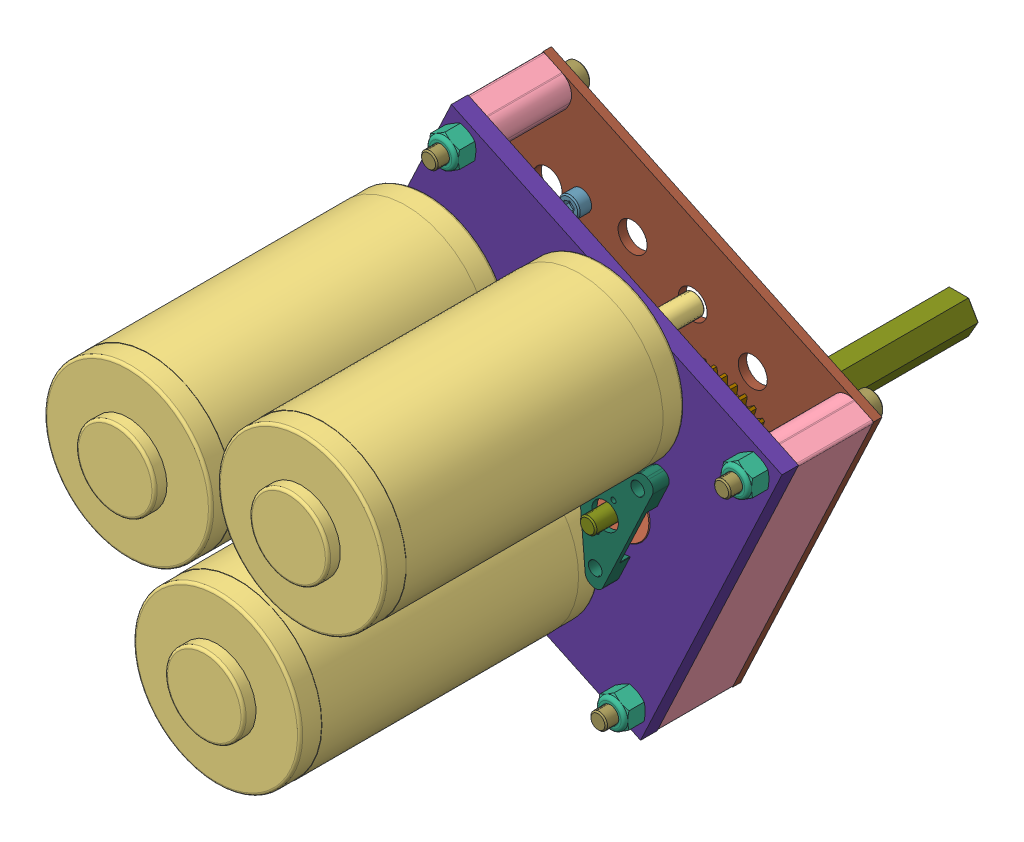
SolidWorks assembly 3CIM Gearbox - AM14U, configuration Default. Lengths in mm.
Overall size (180.67 174.39 248.76).
30 component instances, 17 part files, 62 mates.
Components (placement in the parent):
- 500 E-klip-1: 500 E-klip [Default] at (16.1298 77.6456 -43.9601) x (-0.987566 -0.157207 0) z (0 0 1) size (19.07 20.96 1.27)
- FR6ZZ Bearing-1: FR6ZZ Bearing [Default] at (-13.0875 102.2889 -55.8473) x (0.991783 0.127931 0) z (0 0 -1) size (24.69 24.69 7.16)
- CIM Motor SW-1: CIM Motor SW [Default] at (-100.8929 87.6226 -3.2185) x (0 1 0) z (0 0 -1) size (64.01 64.01 154.94)
- ex-2508 Spacer-1: ex-2508 Spacer [Default] at (-92.2921 67.2369 -57.3713) x (0.425715 0.904857 0) z (0 0 1) size (127 14.35 28.75)
- CIM Motor SW-2: CIM Motor SW [Default] at (-101.4872 6.1263 -3.2185) x (-0.762709 0.646742 0) z (0 0 -1) size (64.01 64.01 154.94)
- Toughbox 14T Small Cluster-1: Toughbox 14T Small Cluster [Default] at (-21.1033 95.1629 -40.7851) x (-0.837052 0.547123 0) z (0 0 -1) size (20.03 20.32 15.25)
- 14-20 Nylock Nut_97135A210-1: 14-20 Nylock Nut_97135A210 [Default] at (19.7748 14.5119 -22.2685) x (1 0 0) z (0 -1 0) size (11.11 8.13 12.83)
- Toughbox 50T Large Cluster-1: Toughbox 50T Large Cluster [Default] at (-21.1033 95.1629 -40.7851) x (-0.055297 -0.99847 0) z (0 0 1) size (65.97 66.04 10.34)
- 10-32 Nylock Jam Nut_90633A411-1: 10-32 Nylock Jam Nut_90633A411 [Default] at (-34.2188 136.4219 -60.5463) x (0.976554 -0.215274 0) z (0.215274 0.976554 0) size (9.53 4.55 11)
- 14-20 Nylock Nut_97135A210-2: 14-20 Nylock Nut_97135A210 [Default] at (67.0932 115.0872 -22.2685) x (1 0 0) z (0 -1 0) size (11.11 8.13 12.83)
- 14-20 Nylock Nut_97135A210-3: 14-20 Nylock Nut_97135A210 [Default] at (-92.2921 67.2369 -22.2685) x (1 0 0) z (0 -1 0) size (11.11 8.13 12.83)
- ex-2508 Spacer-2: ex-2508 Spacer [Default] at (67.0932 115.0872 -57.3713) x (-0.425715 -0.904857 0) z (0 0 1) size (127 14.35 28.75)
- Toughbox 50T Output-1: Toughbox 50T Output [Default] at (16.1298 77.6456 -45.1793) x (1 0 0) z (0 0 -1) size (65.97 66.04 10.62)
- FR6ZZ Bearing-2: FR6ZZ Bearing [Default] at (-30.482 100.3659 -30.1425) x (-0.995778 -0.091798 0) z (0 0 1) size (24.69 24.69 7.16)
- FR8ZZ Hex Bearing-1: FR8ZZ Hex Bearing [Default] at (16.1298 77.6456 -63.2666) size (31.12 31.12 7.93)
- FR6ZZ Bearing-3: FR6ZZ Bearing [Default] at (7.2113 83.6032 -29.1773) x (-0.999955 -0.009486 0) z (0 0 1) size (24.69 24.69 7.16)
- 3CIM TB Special Shaft Plate-1: 3CIM TB Special Shaft Plate [Default] at (16.1298 77.6456 -57.3713) x (0.425715 0.904857 0) z (0 0 1) size (127 139.7 3.17)
- 10-32 Nylock Jam Nut_90633A411-2: 10-32 Nylock Jam Nut_90633A411 [Default] at (-61.2517 78.9634 -60.5463) x (0.733502 -0.679687 0) z (0.679687 0.733502 0) size (9.53 4.55 11)
- SHCS 14-20 x 2-1: SHCS 14-20 x 2 [Default] at (-44.9737 167.8122 -67.0995) x (0.867127 -0.498087 0) z (0.498087 0.867127 0) size (9.53 57.35 9.53)
- CIM Motor SW-3: CIM Motor SW [Default] at (-138.5887 47.3684 -3.2185) x (0.249226 0.968445 0) z (0 0 -1) size (64.01 64.01 154.94)
- SHCS 14-20 x 2-2: SHCS 14-20 x 2 [Default] at (67.0932 115.0872 -67.0995) x (1 0 0) z (0 1 0) size (9.53 57.35 9.53)
- TB Hex Shaft-1: TB Hex Shaft [Default] at (-63.6271 92.3312 -31.1331) x (-0.892349 -0.451347 0) z (-0.451347 0.892349 0) size (11 38.23 9.52)
- 10-32x0625_shcs_HX-SHCS 0.19-32x1.375x1-C-1: 10-32x0625_shcs_HX-SHCS 0.19-32x1.375x1-C [Default] at (-34.2188 136.4219 -52.5453) x (0 0 -1) z (0.658531 0.752554 0) size (20.7 7.94 7.94)
- Toughbox d29a-1: Toughbox d29a [Default] at (16.1298 77.6456 -22.2685) x (-0.904857 0.425715 0) z (0.425715 0.904857 0) size (19.05 6.1 50.8)
- SHCS 14-20 x 2-3: SHCS 14-20 x 2 [Default] at (19.7748 14.5119 -67.0995) x (1 0 0) z (0 1 0) size (9.53 57.35 9.53)
- 14-20 Nylock Nut_97135A210-4: 14-20 Nylock Nut_97135A210 [Default] at (-44.9737 167.8122 -22.2685) x (1 0 0) z (0 -1 0) size (11.11 8.13 12.83)
- TB Output Shaft Hex L-Base 2-1: TB Output Shaft Hex L-Base 2 [Default] at (20.8476 119.155 -54.5773) x (0.5 0.866025 0) z (-0.866025 0.5 0) size (14.66 142.29 12.7)
- 3CIM TB Special Motor Plate-1: 3CIM TB Special Motor Plate [Default] at (16.1298 77.6456 -57.1935) x (0.425715 0.904857 0) z (0 0 1) size (127 139.7 6.35)
- 10-32x0625_shcs_HX-SHCS 0.19-32x1.375x1-C-2: 10-32x0625_shcs_HX-SHCS 0.19-32x1.375x1-C [Default] at (-61.2517 78.9634 -52.5453) x (0 0 -1) z (1 0 0) size (20.7 7.94 7.94)
- SHCS 14-20 x 2-4: SHCS 14-20 x 2 [Default] at (-92.2921 67.2369 -67.0995) x (1 0 0) z (0 1 0) size (9.53 57.35 9.53)
Mates (geometry in assembly coordinates):
- Lock21: lock: unknown of 3CIM TB Special Shaft Plate-1; unknown of 10-32x0625_shcs_HX-SHCS 0.19-32x1.375x1-C-2
- Coincident1: coincident anti-aligned: plane of 3CIM TB Special Shaft Plate-1 through (-48.7708 178.3567 -57.3713) normal (0 0 1); circle of 10-32x0625_shcs_HX-SHCS 0.19-32x1.375x1-C-2
- Lock18: lock: unknown of 3CIM TB Special Shaft Plate-1; unknown of 10-32x0625_shcs_HX-SHCS 0.19-32x1.375x1-C-1
- Coincident3: coincident anti-aligned: plane of 3CIM TB Special Shaft Plate-1 through (-48.7708 178.3567 -57.3713) normal (0 0 1); circle of 10-32x0625_shcs_HX-SHCS 0.19-32x1.375x1-C-1
- Lock17: lock: unknown of 10-32 Nylock Jam Nut_90633A411-1; unknown of 10-32x0625_shcs_HX-SHCS 0.19-32x1.375x1-C-1
- Coincident4: coincident anti-aligned: plane of 10-32 Nylock Jam Nut_90633A411-1 through (-35.4027 131.0516 -60.5463) normal (0 0 1); plane of 3CIM TB Special Shaft Plate-1 through (-48.7708 178.3567 -60.5463) normal (0 0 -1)
- Lock19: lock: unknown of 10-32 Nylock Jam Nut_90633A411-2; unknown of 10-32x0625_shcs_HX-SHCS 0.19-32x1.375x1-C-2
- Coincident5: coincident anti-aligned: plane of 3CIM TB Special Shaft Plate-1 through (-48.7708 178.3567 -60.5463) normal (0 0 -1); plane of 10-32 Nylock Jam Nut_90633A411-2 through (-64.9895 74.9297 -60.5463) normal (0 0 1)
- Coincident6: coincident aligned: plane of 3CIM TB Special Shaft Plate-1 through (-48.7708 178.3567 -60.5463) normal (0 0 -1); circle of SHCS 14-20 x 2-1
- Lock9: lock: unknown of 3CIM TB Special Shaft Plate-1; unknown of SHCS 14-20 x 2-1
- Coincident7: coincident aligned: plane of 3CIM TB Special Shaft Plate-1 through (-48.7708 178.3567 -60.5463) normal (0 0 -1); circle of SHCS 14-20 x 2-4
- Lock15: lock: unknown of 3CIM TB Special Shaft Plate-1; unknown of SHCS 14-20 x 2-4
- Coincident8: coincident aligned: plane of 3CIM TB Special Shaft Plate-1 through (-48.7708 178.3567 -60.5463) normal (0 0 -1); circle of SHCS 14-20 x 2-3
- Lock13: lock: unknown of 3CIM TB Special Shaft Plate-1; unknown of SHCS 14-20 x 2-3
- Coincident9: coincident aligned: plane of 3CIM TB Special Shaft Plate-1 through (-48.7708 178.3567 -60.5463) normal (0 0 -1); circle of SHCS 14-20 x 2-2
- Lock11: lock: unknown of 3CIM TB Special Shaft Plate-1; unknown of SHCS 14-20 x 2-2
- Coincident10: coincident aligned: line of ex-2508 Spacer-2 through (77.3134 118.1948 -57.3713) axis (-0.425715 -0.904857 0); line of 3CIM TB Special Shaft Plate-1 through (77.6378 118.8843 -57.3713) axis (-0.425715 -0.904857 0)
- Coincident11: coincident aligned: line of ex-2508 Spacer-2 through (70.467 122.258 -57.3713) axis (0.904857 -0.425715 0); line of 3CIM TB Special Shaft Plate-1 through (-48.7708 178.3567 -57.3713) axis (0.904857 -0.425715 0)
- Coincident12: coincident aligned: line of ex-2508 Spacer-1 through (-48.0813 178.0323 -57.3713) axis (0.904857 -0.425715 0); line of 3CIM TB Special Shaft Plate-1 through (-48.7708 178.3567 -57.3713) axis (0.904857 -0.425715 0)
- Coincident13: coincident aligned: line of ex-2508 Spacer-1 through (-102.5122 64.1293 -57.3713) axis (0.425715 0.904857 0); line of 3CIM TB Special Shaft Plate-1 through (-102.8366 63.4398 -57.3713) axis (0.425715 0.904857 0)
- Coincident14: coincident anti-aligned: line of ex-2508 Spacer-1 through (-49.0952 177.6672 -28.6185) axis (-0.425715 -0.904857 0); line of 3CIM TB Special Motor Plate-1 through (-102.8366 63.4398 -28.6185) axis (0.425715 0.904857 0)
- Coincident15: coincident aligned: line of ex-2508 Spacer-1 through (-48.0813 178.0323 -28.6185) axis (0.904857 -0.425715 0); line of 3CIM TB Special Motor Plate-1 through (-48.7708 178.3567 -28.6185) axis (0.904857 -0.425715 0)
- Lock12: lock: unknown of 14-20 Nylock Nut_97135A210-2; unknown of SHCS 14-20 x 2-2
- Coincident16: coincident anti-aligned: plane of 14-20 Nylock Nut_97135A210-2 through (61.537 124.7109 -22.2685) normal (0 0 -1); plane of 3CIM TB Special Motor Plate-1 through (77.6378 118.8843 -22.2685) normal (0 0 1)
- Lock14: lock: unknown of 14-20 Nylock Nut_97135A210-1; unknown of SHCS 14-20 x 2-3
- Coincident17: coincident anti-aligned: plane of 14-20 Nylock Nut_97135A210-1 through (14.2186 24.1356 -22.2685) normal (0 0 -1); plane of 3CIM TB Special Motor Plate-1 through (77.6378 118.8843 -22.2685) normal (0 0 1)
- Lock16: lock: unknown of 14-20 Nylock Nut_97135A210-3; unknown of SHCS 14-20 x 2-4
- Coincident18: coincident anti-aligned: plane of 14-20 Nylock Nut_97135A210-3 through (-97.8483 76.8606 -22.2685) normal (0 0 -1); plane of 3CIM TB Special Motor Plate-1 through (77.6378 118.8843 -22.2685) normal (0 0 1)
- Lock10: lock: unknown of SHCS 14-20 x 2-1; unknown of 14-20 Nylock Nut_97135A210-4
- Coincident19: coincident anti-aligned: plane of 14-20 Nylock Nut_97135A210-4 through (-50.5299 177.4359 -22.2685) normal (0 0 -1); plane of 3CIM TB Special Motor Plate-1 through (77.6378 118.8843 -22.2685) normal (0 0 1)
- Coincident20: coincident anti-aligned: circle of FR8ZZ Hex Bearing-1; circle of 3CIM TB Special Shaft Plate-1
- Coincident21: coincident anti-aligned: circle of FR6ZZ Bearing-3; circle of 3CIM TB Special Motor Plate-1
- Lock2: lock: unknown of FR6ZZ Bearing-3; unknown of TB Output Shaft Hex L-Base 2-1
- Coincident23: coincident anti-aligned: plane of FR6ZZ Bearing-3 through (16.1298 77.6456 -29.1773) normal (0 0 -1); plane of TB Output Shaft Hex L-Base 2-1 through (5.1313 83.9956 -29.1773) normal (0 0 1)
- Coincident24: coincident anti-aligned: circle of FR6ZZ Bearing-1; circle of 3CIM TB Special Shaft Plate-1
- Coincident26: coincident aligned: circle of FR6ZZ Bearing-2; circle of 3CIM TB Special Motor Plate-1
- Lock5: lock: unknown of FR6ZZ Bearing-1; unknown of TB Hex Shaft-1
- Coincident27: coincident aligned: plane of FR6ZZ Bearing-1 through (-21.1033 95.1629 -63.0101) normal (0 0 -1); plane of TB Hex Shaft-1 through (-21.1033 95.1629 -63.0101) normal (0 0 -1)
- Coincident28: coincident anti-aligned: plane of Toughbox 14T Small Cluster-1 through (-20.7992 100.6538 -40.7851) normal (0.451347 -0.892349 0); plane of TB Hex Shaft-1 through (-25.7064 98.1717 -31.1331) normal (-0.451347 0.892349 0)
- Coincident29: coincident aligned: plane of FR6ZZ Bearing-1 through (-21.1033 95.1629 -55.8473) normal (0 0 1); circle of Toughbox 14T Small Cluster-1
- Coincident32: coincident anti-aligned: plane of Toughbox 14T Small Cluster-1 through (-21.4074 89.6721 -40.7851) normal (-0.451347 0.892349 0); plane of TB Hex Shaft-1 through (-16.5001 92.1541 -31.1331) normal (0.451347 -0.892349 0)
- Coincident34: coincident anti-aligned: plane of Toughbox 14T Small Cluster-1 through (-16.196 97.645 -40.7851) normal (-0.547123 -0.837052 0); plane of TB Hex Shaft-1 through (-20.7992 100.6538 -31.1331) normal (0.547123 0.837052 0)
- Coincident35: coincident anti-aligned: plane of Toughbox 50T Output-1 through (23.4621 77.6456 -45.1793) normal (-0.866025 -0.5 0); plane of TB Output Shaft Hex L-Base 2-1 through (19.796 83.9956 -29.1773) normal (0.866025 0.5 0)
- Lock1: lock: unknown of Toughbox 50T Output-1; unknown of FR8ZZ Hex Bearing-1
- Coincident37: coincident anti-aligned: plane of Toughbox 50T Output-1 through (23.4621 77.6456 -45.1793) normal (-0.866025 -0.5 0); plane of TB Output Shaft Hex L-Base 2-1 through (19.796 83.9956 -29.1773) normal (0.866025 0.5 0)
- Coincident38: coincident anti-aligned: plane of Toughbox 50T Output-1 through (23.4621 77.6456 -45.1793) normal (-0.866025 -0.5 0); plane of TB Output Shaft Hex L-Base 2-1 through (19.796 83.9956 -29.1773) normal (0.866025 0.5 0)
- Coincident39: coincident anti-aligned: plane of Toughbox 50T Output-1 through (19.796 71.2956 -45.1793) normal (-0.866025 0.5 0); plane of TB Output Shaft Hex L-Base 2-1 through (23.4621 77.6456 -29.1773) normal (0.866025 -0.5 0)
- Lock3: lock: unknown of 500 E-klip-1; unknown of TB Output Shaft Hex L-Base 2-1
- Coincident40: coincident anti-aligned: plane of 500 E-klip-1 through (16.1298 77.6456 -43.9601) normal (0 0 -1); plane of TB Output Shaft Hex L-Base 2-1 through (18.9238 82.4849 -43.9601) normal (0 0 1)
- Coincident41: coincident: line of Toughbox 50T Large Cluster-1 through (-21.4074 89.6721 -40.7851) axis (0.892349 0.451347 0); plane of TB Hex Shaft-1 through (-16.5001 92.1541 -31.1331) normal (0.451347 -0.892349 0)
- Coincident42: coincident: line of Toughbox 50T Large Cluster-1 through (-16.196 97.645 -40.7851) axis (-0.837052 0.547123 0); plane of TB Hex Shaft-1 through (-20.7992 100.6538 -31.1331) normal (0.547123 0.837052 0)
- Coincident43: coincident anti-aligned: plane of Toughbox 14T Small Cluster-1 through (-21.1033 95.1629 -40.7851) normal (0 0 1); plane of Toughbox 50T Large Cluster-1 through (-21.1033 95.1629 -40.7851) normal (0 0 -1)
- Lock23: lock: unknown of FR6ZZ Bearing-3; unknown of Toughbox d29a-1
- Lock24: lock: unknown of Toughbox d29a-1; unknown of 3CIM TB Special Motor Plate-1
- Coincident45: coincident anti-aligned: plane of Toughbox d29a-1 through (35.5617 96.574 -22.2685) normal (0 0 -1); plane of 3CIM TB Special Motor Plate-1 through (77.6378 118.8843 -22.2685) normal (0 0 1)
- Lock8: lock: unknown of CIM Motor SW-1; unknown of 3CIM TB Special Motor Plate-1
- Coincident46: coincident anti-aligned: plane of CIM Motor SW-1 through (8.4033 123.1826 -22.2685) normal (0 0 -1); plane of 3CIM TB Special Motor Plate-1 through (77.6378 118.8843 -22.2685) normal (0 0 1)
- Lock6: lock: unknown of CIM Motor SW-2; unknown of 3CIM TB Special Motor Plate-1
- Coincident47: coincident anti-aligned: plane of CIM Motor SW-2 through (-57.9226 112.4856 -22.2685) normal (0 0 -1); plane of 3CIM TB Special Motor Plate-1 through (77.6378 118.8843 -22.2685) normal (0 0 1)
- Lock22: lock: unknown of CIM Motor SW-3; unknown of 3CIM TB Special Motor Plate-1
- Coincident48: coincident anti-aligned: plane of CIM Motor SW-3 through (-23.8789 54.5669 -22.2685) normal (0 0 -1); plane of 3CIM TB Special Motor Plate-1 through (77.6378 118.8843 -22.2685) normal (0 0 1)
- Lock4: lock: unknown of FR8ZZ Hex Bearing-1; unknown of 3CIM TB Special Shaft Plate-1
